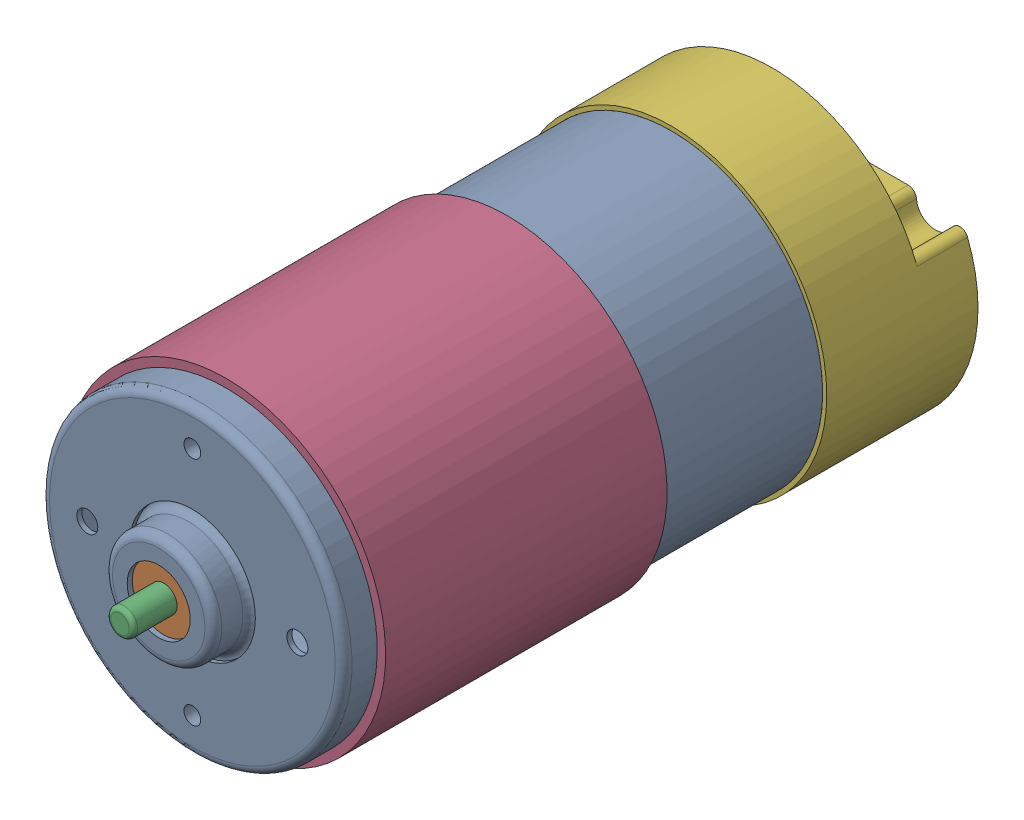
SolidWorks assembly am-3104, configuration Default. Lengths in mm.
Overall size (38 37.8 83.6).
6 component instances, 6 part files, 0 mates.
Components (placement in the parent):
- am-3104-001-1: am-3104-001 [Default] at origin size (36 36 61)
- am-3104-002-1: am-3104-002 [Default] at (0 0 29.9) size (12 12 4)
- am-3104-003-1: am-3104-003 [Default] at (0 0 -2.4) size (3.18 3.18 79)
- am-3104-004-1: am-3104-004 [Default] at (0 0 7.75) size (38 37.8 33.5)
- am-3104-005-1: am-3104-005 [Default] at (0 0 -32) size (35 35 11)
- am-3104-006-1: am-3104-006 [Default] at (0 0 -37.5) size (37 37 18)
